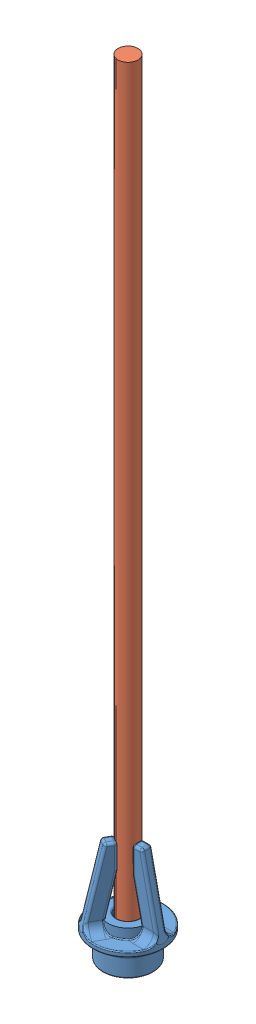
SolidWorks assembly Assem3, configuration Default. Lengths in mm.
Overall size (14 156 14).
2 component instances, 2 part files, 5 mates.
Components (placement in the parent):
- Chuck Base-1: Chuck Base [Default] at origin size (14 21 14)
- whisker 4x150mm-1: whisker 4x150mm [Default] at (0 75 0) x (0.979808 0 0.199942) z (0 1 0) size (4 4 150)
Mates (geometry in assembly coordinates):
- Coincident1: coincident aligned: plane of Chuck Base-1 through (0 0 0) normal (0 0 1)
- Coincident2: coincident aligned: plane of Chuck Base-1 through (0 0 0) normal (0 1 0)
- Coincident3: coincident aligned: plane of Chuck Base-1 through (0 0 0) normal (1 0 0)
- Concentric1: concentric: cylinder of Chuck Base-1 through (0 2 0) axis (0 -1 0) radius 2.25; cylinder of whisker 4x150mm-1 through (0 150 0) axis (0 -1 0) radius 2
- Coincident4: coincident anti-aligned: plane of Chuck Base-1 through (7 0 0) normal (0 1 0); plane of whisker 4x150mm-1 through (0 0 0) normal (0 -1 0)
